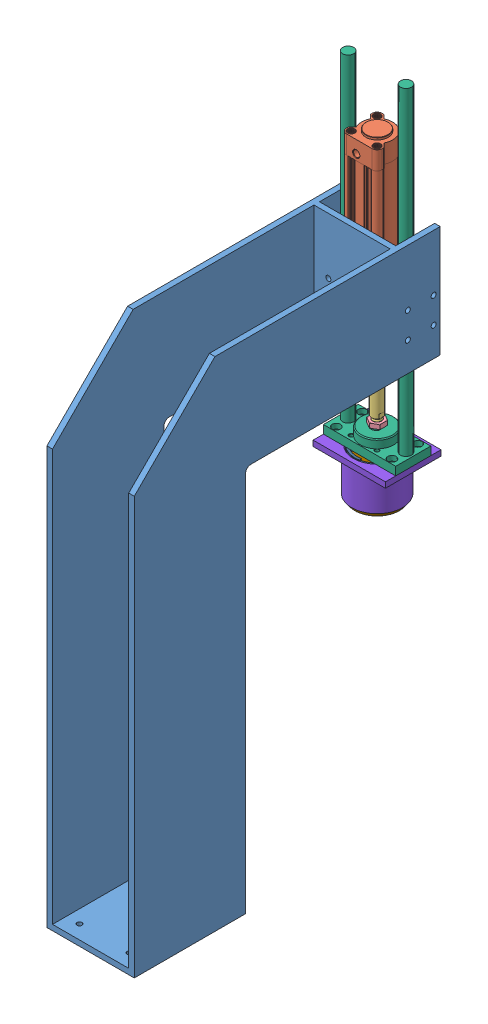
SolidWorks assembly Montagem prensa, configuration Default. Lengths in mm.
Overall size (157 1121.2 565).
15 component instances, 10 part files, 10 mates.
Components (placement in the parent):
- Suporte prensa-1: Suporte prensa [Default] at (129.4691 60.9907 640.0637) size (157 895 550)
- Prensa com suporte especial-1: Prensa com suporte especial [Default] at (60.9691 826.9907 125.0637) x (1 0 0) z (0 -1 0) size (137 70 588) (flexible)
  - 1463770_DSBC_50_150_PPSA__Z_0_-1: 1463770_DSBC_50_150_PPSA__Z_0_ [Default] at origin size (64 64 286.8)
  - 1463770_DSBC_50_150__K_-1: 1463770_DSBC_50_150__K_ [Default] at (0 0 150) size (50 50 290.8)
  - DIN_439_B___M16x1_5_F_-1: DIN_439_B___M16x1_5_F_ [Default] at (0 0 199.8) x (1 0 0) z (0 -1 0) size (24 8 27.71)
  - 150292 FENG-50-400-KF---(asm_0)-1: 150292 FENG-50-400-KF---(asm_0) [Default] at origin size (137 70 588) (flexible)
    - 150292 FENG-50-KF---(GK)-1: 150292 FENG-50-KF---(GK) [Default] at origin size (137 70 150)
    - 150292 FENG-50-400-KF---(JS)-1: 150292 FENG-50-400-KF---(JS) [Default] at (0 0 143.8) size (130 63 588)
    - DIN-912 - M8x40(F)-1: DIN-912 - M8x40(F) [Default] at (23.25 23.25 26) x (1 0 0) z (0 -1 0) size (13 48.35 13)
    - DIN-912 - M8x40(F)-2: DIN-912 - M8x40(F) [Default] at (-23.25 23.25 26) x (1 0 0) z (0 -1 0) size (13 48.35 13)
    - DIN-912 - M8x40(F)-3: DIN-912 - M8x40(F) [Default] at (23.25 -23.25 26) x (1 0 0) z (0 -1 0) size (13 48.35 13)
    - DIN-912 - M8x40(F)-4: DIN-912 - M8x40(F) [Default] at (-23.25 -23.25 26) x (1 0 0) z (0 -1 0) size (13 48.35 13)
- Ponta_prensa-1: Ponta_prensa [Default] at (60.9691 594.1907 125.0637) x (-1 0 0) z (0 0 1) size (130 75 100)
- pino_prensa-1: pino_prensa [Default] at (60.9691 569.1907 125.0637) x (0 -1 0) z (-0.04225 0 0.999107) size (57.5 85 85)
- mola_presa-1: mola_presa [Default] at (60.9691 569.1907 125.0637) x (0.980196 0 -0.198031) z (0.198031 0 0.980196) size (82.37 29.25 81.45)
Mates (geometry in assembly coordinates):
- Coincident1: coincident anti-aligned: plane of Suporte prensa-1 through (129.4691 60.9907 160.0637) normal (0 0 -1); plane of Prensa com suporte especial-1/150292 FENG-50-400-KF---(asm_0)-1/150292 FENG-50-KF---(GK)-1 through (94.9691 826.9907 160.0637) normal (0 0 1)
- Coincident2: coincident anti-aligned: plane of Suporte prensa-1 through (129.4691 -505.8153 90.0637) normal (-1 0 0); plane of Prensa com suporte especial-1/150292 FENG-50-400-KF---(asm_0)-1/150292 FENG-50-KF---(GK)-1 through (129.4691 755.9907 160.0637) normal (1 0 0)
- Concentric1: concentric aligned: cylinder of Suporte prensa-1 through (-17.5309 808.1907 148.3137) axis (1 0 0) radius 4.5; cylinder of Prensa com suporte especial-1/150292 FENG-50-400-KF---(asm_0)-1/150292 FENG-50-KF---(GK)-1 through (129.4691 808.1907 148.3137) axis (1 0 0) radius 3.3235
- Coincident3: coincident anti-aligned: plane of Prensa com suporte especial-1/150292 FENG-50-400-KF---(asm_0)-1/150292 FENG-50-400-KF---(JS)-1 through (60.9691 594.1907 125.0637) normal (0 -1 0); plane of Ponta_prensa-1 through (60.9691 594.1907 125.0637) normal (0 1 0)
- Concentric2: concentric anti-aligned: cylinder of Ponta_prensa-1 through (10.9691 584.1907 101.8137) axis (0 -1 0) radius 3.4; cylinder of Prensa com suporte especial-1/150292 FENG-50-400-KF---(asm_0)-1/150292 FENG-50-400-KF---(JS)-1 through (10.9691 609.1907 101.8137) axis (0 1 0) radius 4.5
- Concentric3: concentric anti-aligned: cylinder of Prensa com suporte especial-1/150292 FENG-50-400-KF---(asm_0)-1/150292 FENG-50-400-KF---(JS)-1 through (110.9691 609.1907 101.8137) axis (0 1 0) radius 4.5; cylinder of Ponta_prensa-1 through (110.9691 584.1907 101.8137) axis (0 -1 0) radius 3.4
- Concentric4: concentric anti-aligned: cylinder of Ponta_prensa-1 through (60.9691 594.1907 125.0637) axis (0 -1 0) radius 41; cylinder of pino_prensa-1 through (60.9691 569.1907 125.0637) axis (0 1 0) radius 41
- Coincident4: coincident anti-aligned: plane of Ponta_prensa-1 through (60.9691 559.1907 125.0637) normal (0 1 0); plane of pino_prensa-1 through (101.9325 559.1907 126.796) normal (0 -1 0)
- Concentric5: concentric aligned: cylinder of Ponta_prensa-1 through (60.9691 519.1907 125.0637) axis (0 1 0) radius 45.5; circle of mola_presa-1
- Coincident5: coincident anti-aligned: plane of pino_prensa-1 through (103.4312 569.1907 126.8593) normal (0 1 0); plane of mola_presa-1 through (60.9691 569.1907 125.0637) normal (0 -1 0)
